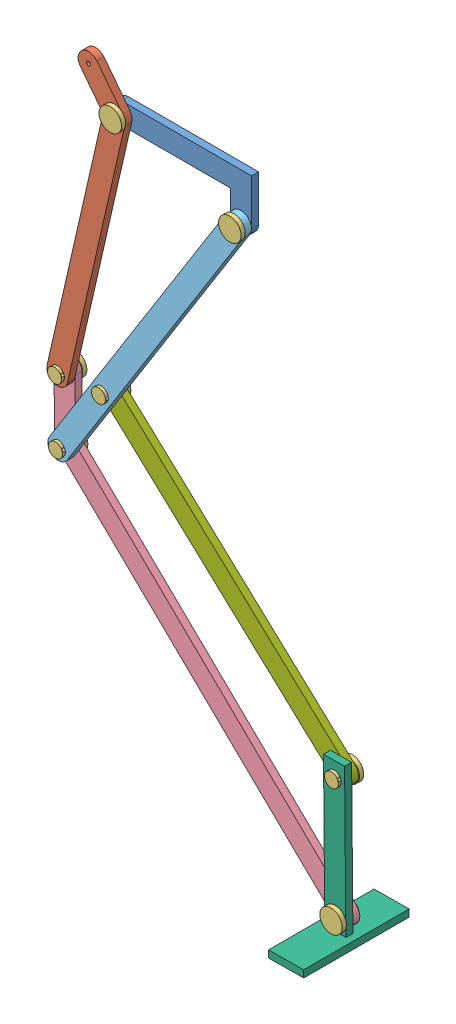
SolidWorks assembly Assem3, configuration Default. Lengths in mm.
Overall size (241.83 460.89 75).
13 component instances, 7 part files, 15 mates.
Components (placement in the parent):
- dlpart2-1: dlpart2 [Default] at (48.414 65.7148 61.7166) size (100 40 5)
- dlpart3(20cm)-1: dlpart3(20cm) [Default] at (-47.6759 -84.0733 66.7166) x (0.222047 0.975036 0) z (0 0 1) size (217.04 38.18 5)
- nutjsdvbg-2: nutjsdvbg [Default] at (-17.3693 56.4102 49.6281) x (0 0 -1) z (0.923728 0.383049 0) size (15 16 16)
- dlpart4(10-20cm)-3: dlpart4(10-20cm) [Default] at (32.7704 -154.5409 66.7166) x (0.999885 0.015153 0) z (0 0 -1) size (209.03 254.63 5)
- nutjsdvbg-5: nutjsdvbg [Default] at (-58.0039 -122.0214 83.8051) x (0 0 1) z (-0.923728 -0.383049 0) size (15 16 16)
- dlpart1-2: dlpart1 [Default] at (77.9704 33.7747 66.7166) x (0.531675 0.846949 0) z (0 0 1) size (250 15 5)
- nutjsdvbg-6: nutjsdvbg [Default] at (67.6307 31.4102 49.6281) x (0 0 -1) z (1 0 0) size (15 16 16)
- nutjsdvbg-7: nutjsdvbg [Default] at (-57.3128 -167.6228 83.8051) x (0 0 1) z (-0.923728 -0.383049 0) size (15 16 16)
- dltshape-1: dltshape [Default] at (143.4929 -371.653 153.5983) x (0 0 -1) z (0.999962 0.008671 0) size (75 110 25)
- nutjsdvbg-8: nutjsdvbg [Default] at (139.6304 -358.686 49.6281) x (0 0 -1) z (0.923728 0.383049 0) size (15 16 16)
- dlpartlast-1: dlpartlast [Default] at (69.5093 -218.5156 66.7166) x (-0.732859 0.68038 0) z (0 0 -1) size (241 15 5)
- nutjsdvbg-9: nutjsdvbg [Default] at (-26.7415 -118.9232 83.8051) x (0 0 1) z (-1 0 0) size (15 16 16)
- nutjsdvbg-10: nutjsdvbg [Default] at (138.8847 -272.6892 83.8051) x (0 0 1) z (-0.923728 -0.383049 0) size (15 16 16)
Mates (geometry in assembly coordinates):
- Coincident4: coincident aligned: circle of dlpart2-1; circle of dlpart3(20cm)-1
- Coincident5: coincident aligned: circle of dlpart3(20cm)-1; circle of nutjsdvbg-2
- Coincident15: coincident anti-aligned: circle of dlpart3(20cm)-1; circle of dlpart4(10-20cm)-3
- Coincident16: coincident aligned: circle of dlpart4(10-20cm)-3; circle of nutjsdvbg-5
- Coincident21: coincident anti-aligned: circle of dlpart2-1; circle of dlpart1-2
- Coincident22: coincident anti-aligned: circle of dlpart1-2; circle of nutjsdvbg-6
- Coincident23: coincident anti-aligned: circle of dlpart4(10-20cm)-3; circle of dlpart1-2
- Coincident24: coincident aligned: circle of dlpart4(10-20cm)-3; circle of nutjsdvbg-7
- Coincident25: coincident anti-aligned: cylinder of dlpart4(10-20cm)-3; cylinder of dltshape-1 through (139.6304 -358.686 31.7166) axis (0 0 1) radius 5
- Coincident26: coincident anti-aligned: circle of dlpart4(10-20cm)-3; circle of dltshape-1
- Coincident27: coincident aligned: circle of dltshape-1; circle of nutjsdvbg-8
- Coincident28: coincident aligned: circle of dlpart1-2; circle of dlpartlast-1
- Coincident29: coincident anti-aligned: circle of dlpartlast-1; circle of nutjsdvbg-9
- Coincident30: coincident anti-aligned: circle of dltshape-1; circle of dlpartlast-1
- Coincident31: coincident aligned: circle of dlpartlast-1; circle of nutjsdvbg-10
